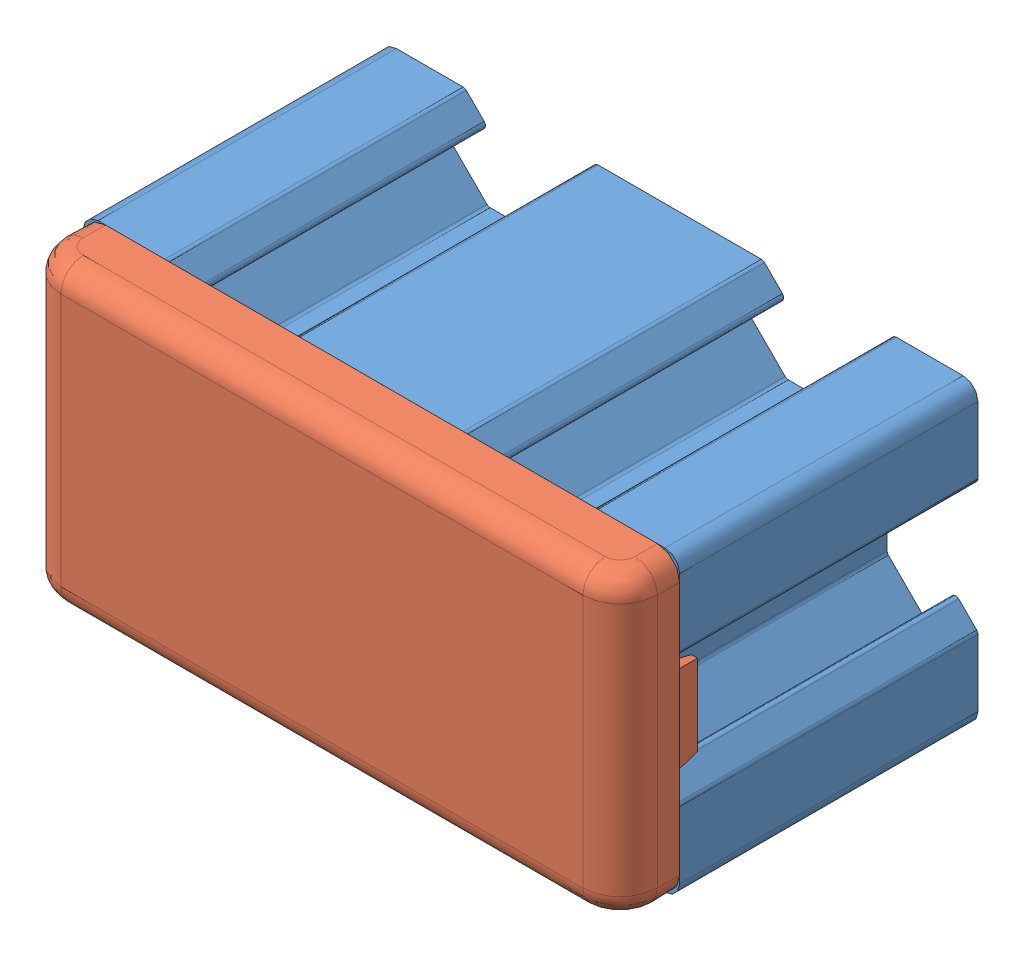
SolidWorks assembly Заглушка20х40СБ, configuration По умолчанию. Lengths in mm.
Overall size (40 20 24).
2 component instances, 2 part files, 6 mates.
Components (placement in the parent):
- 20х40V заглушка-1: 20х40V заглушка [По умолчанию] at origin size (40 20 20)
- Заглушка торцевая 20х40-1: Заглушка торцевая 20х40 [По умолчанию] at (10 0 22) x (0 0 -1) z (0 1 0) size (8 40 20)
Mates (geometry in assembly coordinates):
- Совпадение2: coincident: point of 20х40V заглушка-1
- Параллельность1: parallel anti-aligned: plane of 20х40V заглушка-1 through (15.6 -10 20) normal (0 -1 0)
- Совпадение4: coincident anti-aligned: plane of 20х40V заглушка-1 through (0 0 0) normal (0 0 -1)
- Совпадение5: coincident anti-aligned: plane of 20х40V заглушка-1 through (0 0 20) normal (0 0 1); plane of Заглушка торцевая 20х40-1 through (30 -10 20) normal (0 0 -1)
- Совпадение6: coincident aligned: plane of 20х40V заглушка-1 through (15.6 10 20) normal (0 1 0); plane of Заглушка торцевая 20х40-1 through (-7.5 10 21.5) normal (0 1 0)
- Совпадение7: coincident aligned: plane of 20х40V заглушка-1 through (30 10 20) normal (1 0 0); plane of Заглушка торцевая 20х40-1 through (30 -10 21.5) normal (1 0 0)
